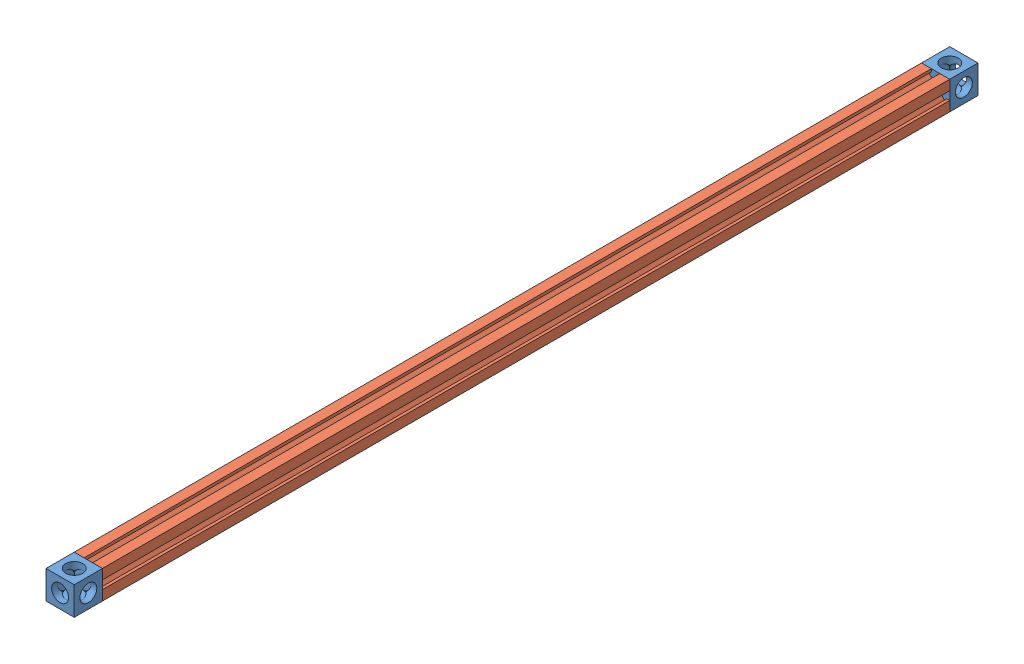
SolidWorks assembly BigRobotMakerBeamFrame, configuration Default. Lengths in mm.
Overall size (10 10 320).
3 component instances, 2 part files, 6 mates.
Components (placement in the parent):
- MakerBeam-cube-1: MakerBeam-cube [Default] at (-29.6175 -5.1709 14.1418) size (10 10 10)
- Makerbeam50-1000mm-1: Makerbeam50-1000mm [300mm] at (-29.6175 -5.1709 -285.8582) size (10 10 300)
- MakerBeam-cube-2: MakerBeam-cube [Default] at (-34.6175 -5.1709 -290.8582) x (0 0 -1) z (1 0 0) size (10 10 10)
Mates (geometry in assembly coordinates):
- Coincident1: coincident anti-aligned: plane of MakerBeam-cube-1 through (-29.6175 -5.1709 14.1418) normal (0 0 -1); plane of Makerbeam50-1000mm-1 through (-29.6175 -5.1709 14.1418) normal (0 0 1)
- Coincident2: coincident aligned: plane of MakerBeam-cube-1 through (-24.6175 -10.1709 24.1418) normal (1 0 0); plane of Makerbeam50-1000mm-1 through (-24.6175 -0.1709 14.1418) normal (1 0 0)
- Concentric1: concentric anti-aligned: cylinder of MakerBeam-cube-1 through (-29.6175 -5.1709 24.1418) axis (0 0 1) radius 1.25; cylinder of Makerbeam50-1000mm-1 through (-29.6175 -5.1709 14.1418) axis (0 0 -1) radius 1.25
- Coincident3: coincident anti-aligned: plane of Makerbeam50-1000mm-1 through (-29.6175 -5.1709 -285.8582) normal (0 0 -1); plane of MakerBeam-cube-2 through (-24.6175 -10.1709 -285.8582) normal (0 0 1)
- Concentric2: concentric aligned: cylinder of Makerbeam50-1000mm-1 through (-29.6175 -5.1709 14.1418) axis (0 0 -1) radius 1.25; cylinder of MakerBeam-cube-2 through (-29.6175 -5.1709 -295.8582) axis (0 0 -1) radius 1.25
- Coincident6: coincident aligned: plane of Makerbeam50-1000mm-1 through (-34.6175 -10.1709 14.1418) normal (-1 0 0); plane of MakerBeam-cube-2 through (-34.6175 -5.1709 -290.8582) normal (-1 0 0)
